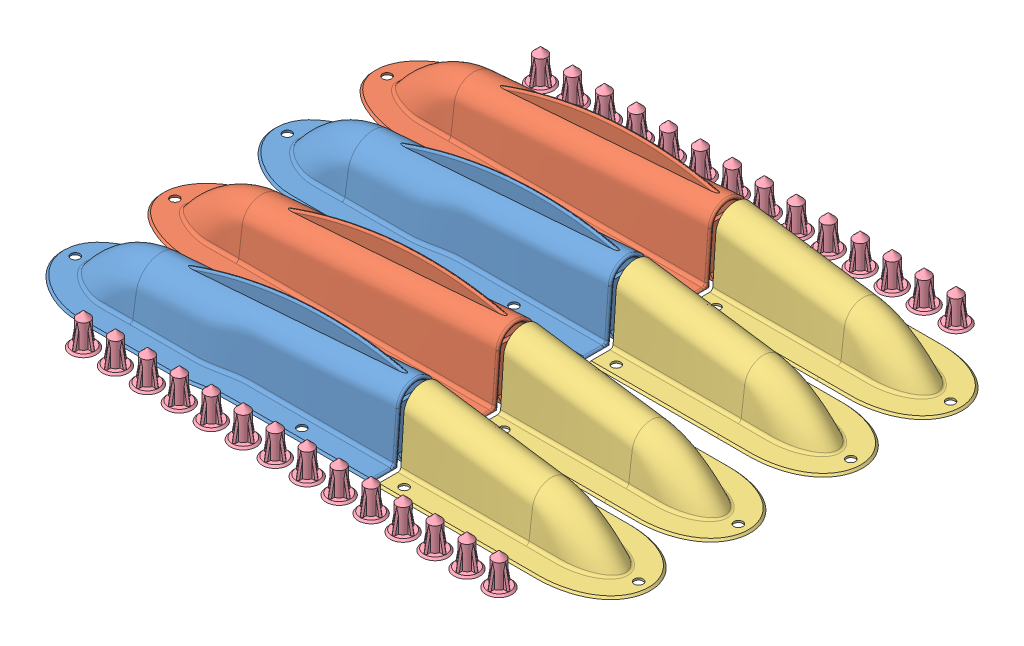
SolidWorks assembly ServoProtectorPlate, configuration Default. Lengths in mm.
Overall size (184.01 26.23 151.05).
36 component instances, 4 part files, 30 mates.
Components (placement in the parent):
- AileronServoProtector-Left-1: AileronServoProtector-Left [Default] at (-79.9998 0 164.2195) x (1 0 0.000012) z (-0.000012 0 1) size (111.59 26.23 31.26)
- AileronServoProtector-Right-1: AileronServoProtector-Right [Default] at (-79.9998 0 133.0287) x (1 0 -0.000012) z (0.000012 0 1) size (111.59 26.23 31.26)
- AileronServoProtector-Left-2: AileronServoProtector-Left [Default] at (-79.9998 0 97.8568) x (1 0 0.000012) z (-0.000012 0 1) size (111.59 26.23 31.26)
- AileronServoProtector-Right-2: AileronServoProtector-Right [Default] at (-79.9998 0 66.6659) x (1 0 -0.000012) z (0.000012 0 1) size (111.59 26.23 31.26)
- FlapServoProtectors-1: FlapServoProtectors [Default] at (41.9994 0 66.6577) x (-1 0 -0.000004) z (0.000004 0 -1) size (71.04 21.52 29.2)
- FlapServoProtectors-4: FlapServoProtectors [Default] at (41.9994 0 97.8503) x (-1 0 -0.000004) z (0.000004 0 -1) size (71.04 21.52 29.2)
- FlapServoProtectors-3: FlapServoProtectors [Default] at (41.9994 0 133.0269) x (-1 0 -0.000004) z (0.000004 0 -1) size (71.04 21.52 29.2)
- FlapServoProtectors-2: FlapServoProtectors [Default] at (41.9994 0 164.2195) x (-1 0 -0.000004) z (0.000004 0 -1) size (71.04 21.52 29.2)
- ScrewBase-1: ScrewBase [Default] at (-81.6472 0 186.9959) size (8.05 10.02 8.05)
- ScrewBase-2: ScrewBase [Default] at (-71.6472 0 186.9959) size (8.05 10.02 8.05)
- ScrewBase-3: ScrewBase [Default] at (-61.6472 0 186.9959) size (8.05 10.02 8.05)
- ScrewBase-4: ScrewBase [Default] at (-51.6472 0 186.9959) size (8.05 10.02 8.05)
- ScrewBase-5: ScrewBase [Default] at (-41.6472 0 186.9959) size (8.05 10.02 8.05)
- ScrewBase-6: ScrewBase [Default] at (-31.6472 0 186.9959) size (8.05 10.02 8.05)
- ScrewBase-7: ScrewBase [Default] at (-21.6472 0 186.9959) size (8.05 10.02 8.05)
- ScrewBase-8: ScrewBase [Default] at (-11.6472 0 186.9959) size (8.05 10.02 8.05)
- ScrewBase-9: ScrewBase [Default] at (-1.6472 0 186.9959) size (8.05 10.02 8.05)
- ScrewBase-10: ScrewBase [Default] at (8.3528 0 186.9959) size (8.05 10.02 8.05)
- ScrewBase-11: ScrewBase [Default] at (18.3528 0 186.9959) size (8.05 10.02 8.05)
- ScrewBase-12: ScrewBase [Default] at (28.3528 0 186.9959) size (8.05 10.02 8.05)
- ScrewBase-13: ScrewBase [Default] at (38.3528 0 186.9959) size (8.05 10.02 8.05)
- ScrewBase-14: ScrewBase [Default] at (48.3528 0 186.9959) size (8.05 10.02 8.05)
- ScrewBase-16: ScrewBase [Default] at (-81.6472 0 43.9959) size (8.05 10.02 8.05)
- ScrewBase-17: ScrewBase [Default] at (-71.6472 0 43.9959) size (8.05 10.02 8.05)
- ScrewBase-18: ScrewBase [Default] at (-61.6472 0 43.9959) size (8.05 10.02 8.05)
- ScrewBase-19: ScrewBase [Default] at (-51.6472 0 43.9959) size (8.05 10.02 8.05)
- ScrewBase-20: ScrewBase [Default] at (-41.6472 0 43.9959) size (8.05 10.02 8.05)
- ScrewBase-21: ScrewBase [Default] at (-31.6472 0 43.9959) size (8.05 10.02 8.05)
- ScrewBase-22: ScrewBase [Default] at (-21.6472 0 43.9959) size (8.05 10.02 8.05)
- ScrewBase-23: ScrewBase [Default] at (-11.6472 0 43.9959) size (8.05 10.02 8.05)
- ScrewBase-24: ScrewBase [Default] at (-1.6472 0 43.9959) size (8.05 10.02 8.05)
- ScrewBase-25: ScrewBase [Default] at (8.3528 0 43.9959) size (8.05 10.02 8.05)
- ScrewBase-26: ScrewBase [Default] at (18.3528 0 43.9959) size (8.05 10.02 8.05)
- ScrewBase-27: ScrewBase [Default] at (28.3528 0 43.9959) size (8.05 10.02 8.05)
- ScrewBase-28: ScrewBase [Default] at (38.3528 0 43.9959) size (8.05 10.02 8.05)
- ScrewBase-29: ScrewBase [Default] at (48.3528 0 43.9959) size (8.05 10.02 8.05)
Mates (geometry in assembly coordinates):
- Coincident13: coincident anti-aligned: plane of assembly through (0 0 0) normal (0 1 0); plane of AileronServoProtector-Right-2 through (-103.7682 0 65.5979) normal (0 -1 0)
- Coincident14: coincident anti-aligned: plane of assembly through (0 0 0) normal (0 1 0); plane of AileronServoProtector-Left-2 through (-103.7682 0 98.9249) normal (0 -1 0)
- Coincident15: coincident anti-aligned: plane of assembly through (0 0 0) normal (0 1 0); plane of AileronServoProtector-Right-1 through (-103.7682 0 131.9606) normal (0 -1 0)
- Coincident16: coincident anti-aligned: plane of assembly through (0 0 0) normal (0 1 0); plane of AileronServoProtector-Left-1 through (-103.7682 0 165.2876) normal (0 -1 0)
- Coincident17: coincident anti-aligned: plane of assembly through (0 0 0) normal (0 1 0); plane of FlapServoProtectors-4 through (41.9995 0 90.6503) normal (0 -1 0)
- Coincident18: coincident anti-aligned: plane of assembly through (0 0 0) normal (0 1 0); plane of FlapServoProtectors-3 through (41.9995 0 125.8269) normal (0 -1 0)
- Coincident19: coincident anti-aligned: plane of assembly through (0 0 0) normal (0 1 0); plane of FlapServoProtectors-2 through (41.9995 0 157.0195) normal (0 -1 0)
- Coincident20: coincident anti-aligned: plane of assembly through (0 0 0) normal (0 1 0); plane of FlapServoProtectors-1 through (41.9995 0 59.4577) normal (0 -1 0)
- Coincident21: coincident anti-aligned: plane of assembly through (0 0 0) normal (0 1 0); plane of ScrewBase-1 through (-81.6472 0 186.9959) normal (0 -1 0)
- Coincident22: coincident: plane of assembly through (0 0 0) normal (1 0 0); point of AileronServoProtector-Left-1
- Coincident23: coincident: plane of assembly through (0 0 0) normal (1 0 0); point of AileronServoProtector-Left-1
- Coincident24: coincident: plane of assembly through (0 0 0) normal (1 0 0); point of AileronServoProtector-Right-1
- Coincident25: coincident: plane of assembly through (0 0 0) normal (1 0 0); point of AileronServoProtector-Right-1
- Coincident26: coincident: plane of assembly through (0 0 0) normal (1 0 0); point of AileronServoProtector-Left-2
- Coincident27: coincident: plane of assembly through (0 0 0) normal (1 0 0); point of AileronServoProtector-Left-2
- Coincident28: coincident: plane of assembly through (0 0 0) normal (1 0 0); point of AileronServoProtector-Right-2
- Coincident29: coincident: plane of assembly through (0 0 0) normal (1 0 0); point of AileronServoProtector-Right-2
- Coincident30: coincident: plane of assembly through (2 0 0) normal (1 0 0); point of FlapServoProtectors-2
- Coincident31: coincident: plane of assembly through (2 0 0) normal (1 0 0); point of FlapServoProtectors-2
- Coincident32: coincident: plane of assembly through (2 0 0) normal (1 0 0); point of FlapServoProtectors-3
- Coincident33: coincident: plane of assembly through (2 0 0) normal (1 0 0); point of FlapServoProtectors-3
- Coincident34: coincident: plane of assembly through (2 0 0) normal (1 0 0); point of FlapServoProtectors-4
- Coincident35: coincident: plane of assembly through (2 0 0) normal (1 0 0); point of FlapServoProtectors-4
- Coincident36: coincident: plane of assembly through (2 0 0) normal (1 0 0); point of FlapServoProtectors-1
- Coincident37: coincident: plane of assembly through (2 0 0) normal (1 0 0); point of FlapServoProtectors-1
- Distance2: distance = 2 mm: point of FlapServoProtectors-2; point of FlapServoProtectors-3
- Distance4: distance = 2 mm: point of FlapServoProtectors-4; point of FlapServoProtectors-1
- Distance5: distance = 2 mm: point of AileronServoProtector-Left-1; point of AileronServoProtector-Right-1
- Distance6: distance = 2 mm: point of AileronServoProtector-Left-2; point of AileronServoProtector-Right-2
- Distance7: distance = 2 mm: point of AileronServoProtector-Right-1; point of AileronServoProtector-Left-2
